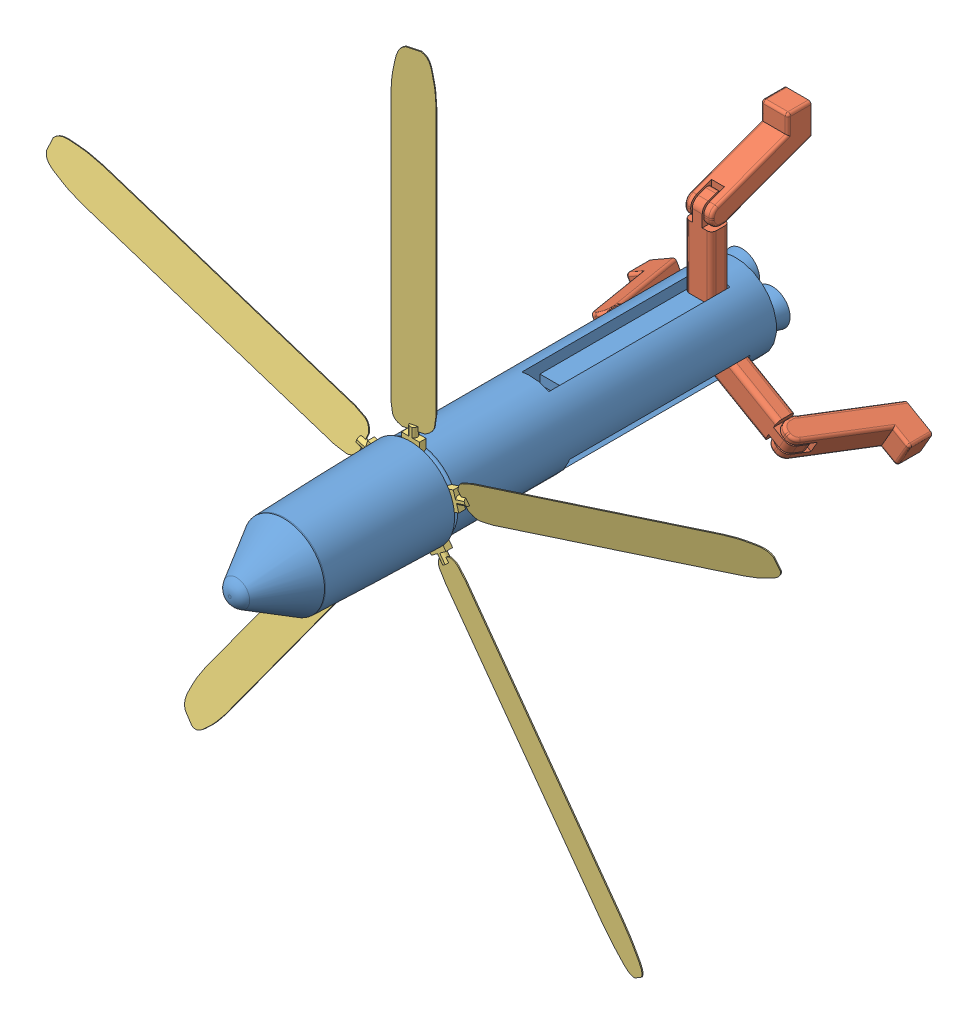
SolidWorks assembly 舱室降落, configuration 默认. Lengths in mm.
Overall size (980.14 980.14 980.14).
9 component instances, 3 part files, 0 mates.
Components (placement in the parent):
- r-1: r [默认] at (-29.3521 18.5175 -75.4152) size (102.41 102.31 578)
- 零件2^舱室降落-1: 零件2^舱室降落 [默认] at origin size (136.17 95.47 110) (virtual)
- 零件2^舱室降落-2: 零件2^舱室降落 [默认] at (-60.0648 2.3566 0) x (-0.5 -0.866025 0) z (0 0 1) size (136.17 95.47 110) (virtual)
- 零件2^舱室降落-3: 零件2^舱室降落 [默认] at (-27.9916 53.1959 0) x (-0.5 0.866025 0) z (0 0 1) size (136.17 95.47 110) (virtual)
- jiang -1: jiang  [默认] at origin size (40.25 381.7 11.23)
- jiang -2: jiang  [默认] at (-37.893 -15.1203 0) x (0.309017 -0.951057 0) z (0 0 1) size (40.25 381.7 11.23)
- jiang -3: jiang  [默认] at (-63.9828 16.2457 0) x (-0.809017 -0.587785 0) z (0 0 1) size (40.25 381.7 11.23)
- jiang -4: jiang  [默认] at (-42.2142 50.7512 0) x (-0.809017 0.587785 0) z (0 0 1) size (40.25 381.7 11.23)
- jiang -5: jiang  [默认] at (-2.6706 40.7108 0) x (0.309017 0.951057 0) z (0 0 1) size (40.25 381.7 11.23)
